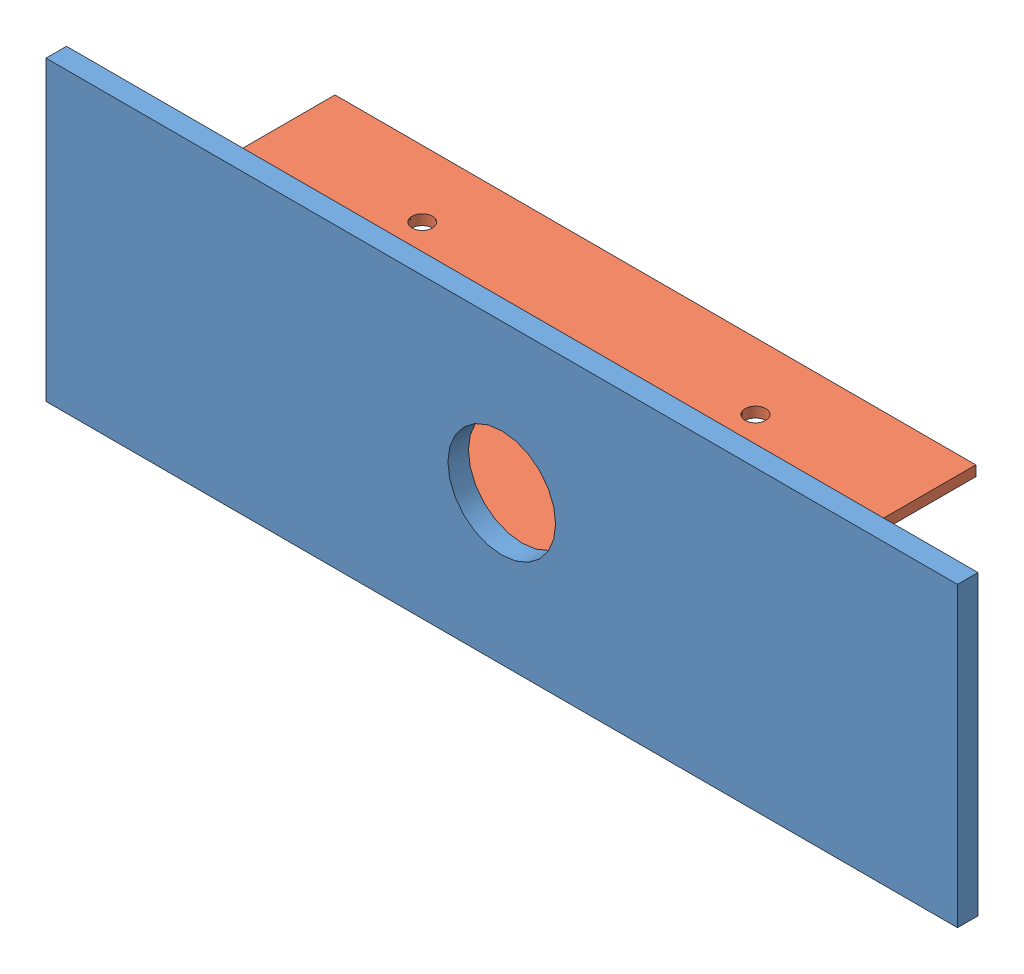
SolidWorks assembly Assem3, configuration Default. Lengths in mm.
Overall size (177.8 58 114.37).
3 component instances, 2 part files, 6 mates.
Components (placement in the parent):
- nerz-1: nerz [Default] at origin size (177.8 58 4)
- ner tvirtinimas-1: ner tvirtinimas [Default] at (1.4666 -18.814 -6.5897) x (0.92388 0 -0.382683) z (0 -1 0) size (125.43 71.84 2)
- ner tvirtinimas-2: ner tvirtinimas [Default] at (1.4666 21.186 -6.5897) x (0.92388 0 -0.382683) z (0 -1 0) size (125.43 71.84 2)
Mates (geometry in assembly coordinates):
- Coincident1: coincident: plane of assembly; plane of assembly; plane of nerz-1 through (0 0 0) normal (0 0 -1); plane of ner tvirtinimas-1 through (-57.2741 -20.814 0) normal (0 0 1)
- Distance1: distance = 8 mm: plane of assembly; plane of assembly; plane of ner tvirtinimas-1 through (1.4666 -20.814 -6.5897) normal (0 -1 0); plane of nerz-1 through (-83.6741 -28.814 4) normal (0 -1 0)
- Width1: width: plane of assembly; plane of assembly; plane of assembly; plane of assembly; plane of ner tvirtinimas-1 through (67.7259 -20.814 -25.9783) normal (1 0 0); plane of ner tvirtinimas-1 through (-57.2741 -20.814 0) normal (-1 0 0); plane of nerz-1 through (-83.6741 29.186 4) normal (-1 0 0); plane of nerz-1 through (94.1259 29.186 4) normal (1 0 0)
- Distance2: distance = 8 mm: plane of assembly; plane of assembly; plane of ner tvirtinimas-2 through (1.4666 21.186 -6.5897) normal (0 1 0); plane of nerz-1 through (-83.6741 29.186 4) normal (0 1 0)
- Coincident4: coincident: plane of assembly; plane of assembly; plane of nerz-1 through (0 0 0) normal (0 0 -1); plane of ner tvirtinimas-2 through (-57.2741 19.186 0) normal (0 0 1)
- Width2: width: plane of assembly; plane of assembly; plane of assembly; plane of assembly; plane of ner tvirtinimas-2 through (67.7259 19.186 -25.9783) normal (1 0 0); plane of ner tvirtinimas-2 through (-57.2741 19.186 0) normal (-1 0 0); plane of nerz-1 through (-83.6741 29.186 4) normal (-1 0 0); plane of nerz-1 through (94.1259 29.186 4) normal (1 0 0)
